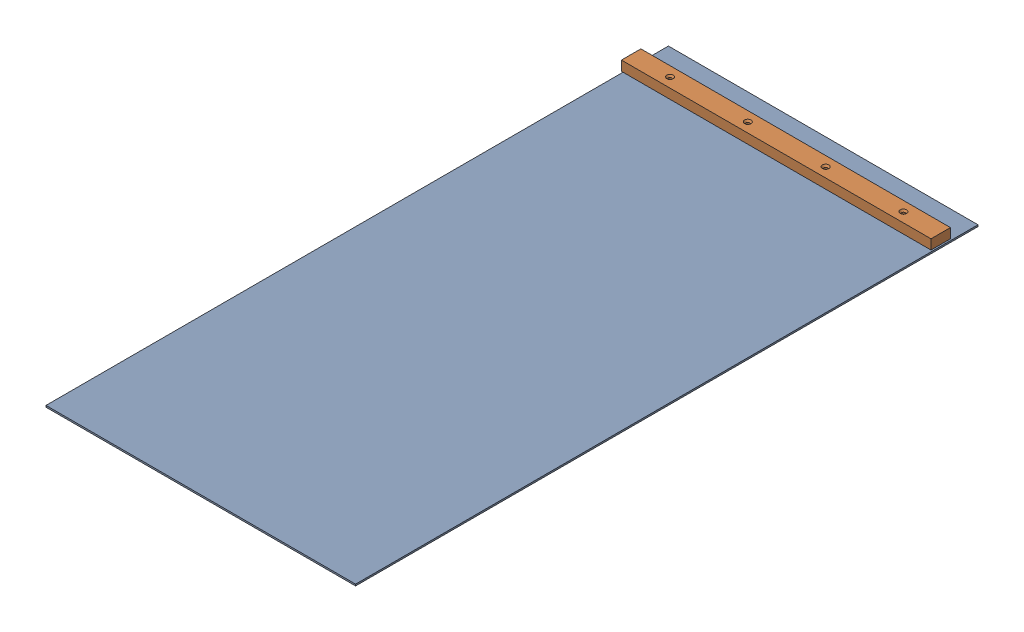
SolidWorks assembly GE-16186_ASM, configuration Default. Lengths in mm.
Overall size (609.6 22.23 1219.2).
2 component instances, 2 part files, 0 mates.
Components (placement in the parent):
- GE-16142-1: GE-16142 [Default] at origin size (606.42 3.17 1219.2)
- GE-16183-1: GE-16183 [Default] at (-3.175 3.175 -1168.4) x (1 0 0) z (0 1 0) size (606.42 38.1 19.05)
